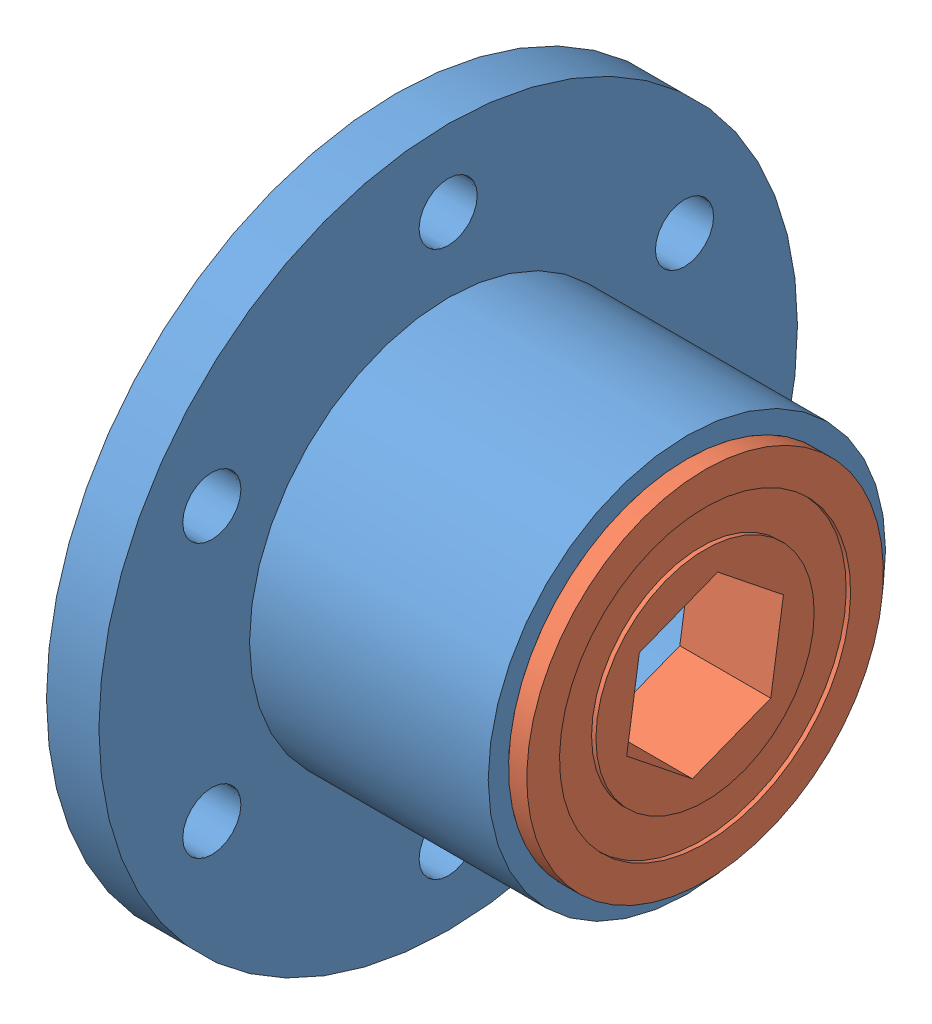
SolidWorks assembly 500 Hex Bearing Hub, configuration Default. Lengths in mm.
Overall size (28.57 60.96 60.96).
3 component instances, 2 part files, 5 mates.
Components (placement in the parent):
- 500 Bearing Hub-1: 500 Bearing Hub [Large opening] at (23.6084 28.818 48.3758) size (25.4 60.96 60.96)
- 5 Hex Bearing 217-2734-1: 5 Hex Bearing 217-2734 [Default] at (17.2584 28.818 48.3758) x (0 -0.363875 0.931448) z (0 -0.931448 -0.363875) size (31.12 7.94 31.12)
- 5 Hex Bearing 217-2734-2: 5 Hex Bearing 217-2734 [Default] at (29.9584 28.818 48.3758) x (0 -0.988595 0.150599) z (0 0.150599 0.988595) size (31.12 7.94 31.12)
Mates (geometry in assembly coordinates):
- Concentric2: concentric aligned: cylinder of 500 Bearing Hub-1 through (10.9084 28.818 48.3758) axis (1 0 0) radius 15.56; cylinder of 5 Hex Bearing 217-2734-2 through (29.9584 28.818 48.3758) axis (1 0 0) radius 14.2748
- Concentric3: concentric anti-aligned: cylinder of 500 Bearing Hub-1 through (10.9084 28.818 48.3758) axis (1 0 0) radius 15.56; cylinder of 5 Hex Bearing 217-2734-1 through (17.2584 28.818 48.3758) axis (-1 0 0) radius 14.2748
- Coincident4: coincident aligned: plane of 5 Hex Bearing 217-2734-1 through (17.2584 26.1458 55.2162) normal (0 -0.150599 -0.988595); plane of 5 Hex Bearing 217-2734-2 through (29.9584 33.4059 54.1102) normal (0 -0.150599 -0.988595)
- Coincident5: coincident anti-aligned: plane of 500 Bearing Hub-1 through (36.3084 28.818 48.3758) normal (1 0 0); plane of 5 Hex Bearing 217-2734-2 through (36.3084 13.438 50.7187) normal (-1 0 0)
- Coincident6: coincident anti-aligned: plane of 500 Bearing Hub-1 through (10.9084 28.818 48.3758) normal (-1 0 0); plane of 5 Hex Bearing 217-2734-1 through (10.9084 23.1571 62.8668) normal (1 0 0)
